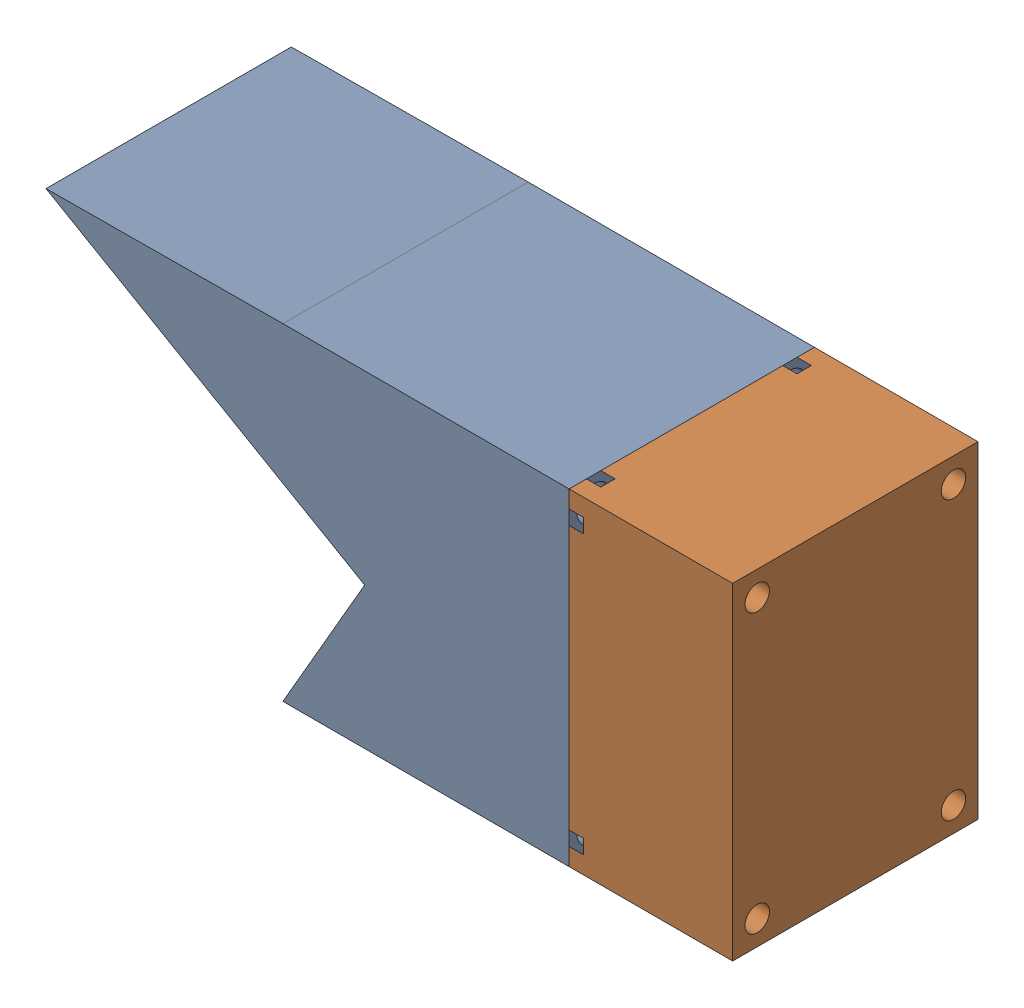
SolidWorks assembly MirrorNacelle Assembly1, configuration Default. Lengths in mm.
Overall size (106.64 50.8 38.1).
2 component instances, 2 part files, 0 mates.
Components (placement in the parent):
- MirrorCalf Nacelle-1: MirrorCalf Nacelle [Default] at (1.6936 15.1916 -38.1993) size (81.24 50.8 38.1)
- MotorEndcap-1: MotorEndcap [Default] at (31.0235 2.2988 -24.7342) x (0 0 1) z (-1 0 0) size (38.1 50.8 25.4)
